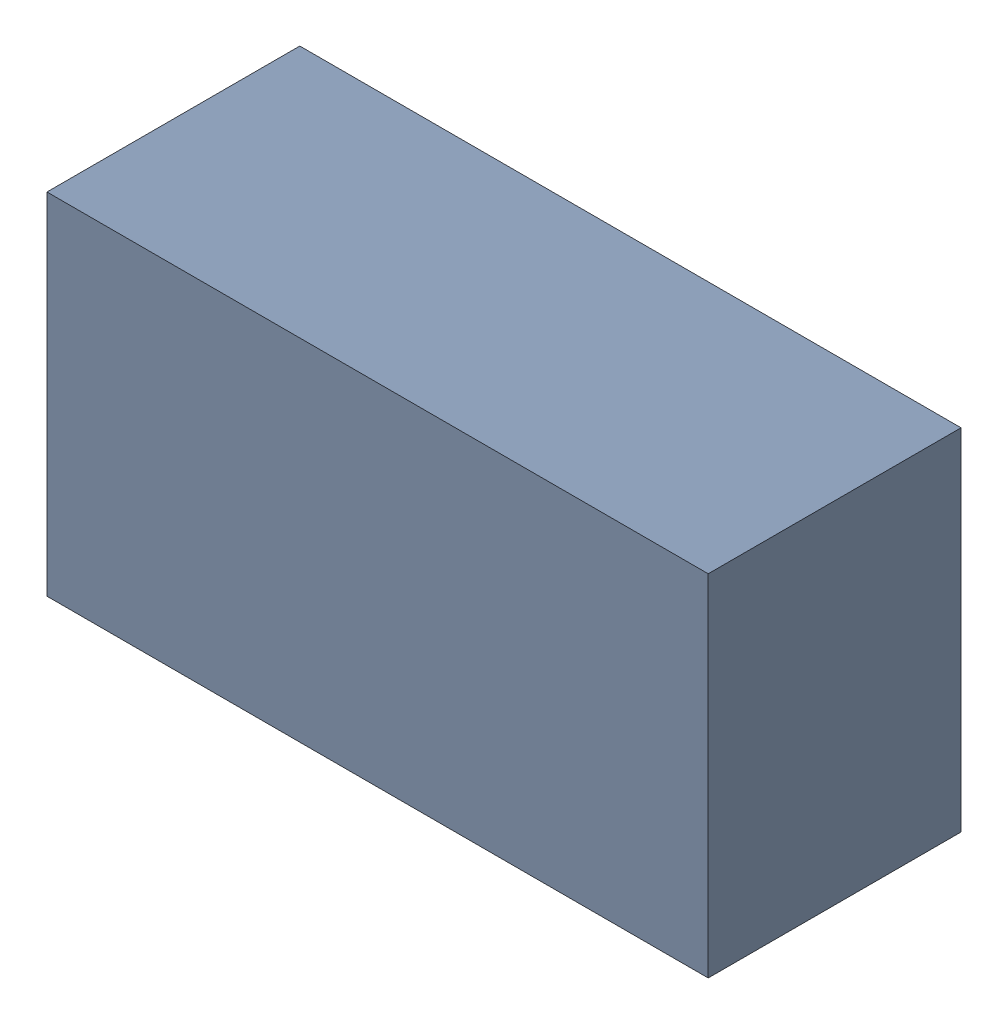
SolidWorks assembly C202, configuration Standard. Lengths in mm.
Overall size (3.4 1.8 1.3).
2 component instances, 1 part files, 0 mates.
Components (placement in the parent):
- 885542104-1: 885542104 [Standard] at (6.3 -24.7 0) size (3.4 1.8 1.3)
  - Extruded_29-1: Extruded_29 [Standard] at origin size (3.4 1.8 1.3)
